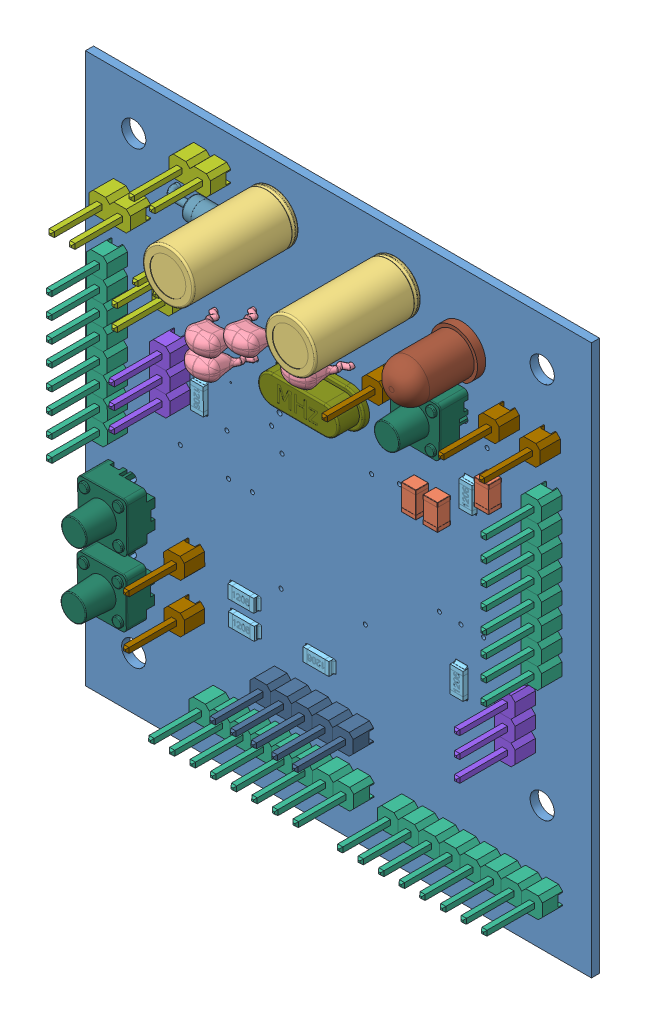
SolidWorks assembly STM32DevBoard, configuration Default. Lengths in mm.
Overall size (62.35 67.78 16.2).
48 component instances, 16 part files, 79 mates.
Components (placement in the parent):
- board^STM32DevBoard-1: board^STM32DevBoard [Default] at origin size (62.35 67.78 1) (virtual)
- CAP 1206-1.8mm^STM32DevBoard-4: CAP 1206-1.8mm^STM32DevBoard [По умолчанию] at (48.0846 53.1145 -0.8) x (1 0 0) z (0 0 -1) size (3.2 1.8 1.6) (virtual)
- CAP 1206-1.8mm^STM32DevBoard-5: CAP 1206-1.8mm^STM32DevBoard [По умолчанию] at (44.5905 35.7089 -0.8) x (1 0 0) z (0 0 -1) size (3.2 1.8 1.6) (virtual)
- CAP 1206-1.8mm^STM32DevBoard-6: CAP 1206-1.8mm^STM32DevBoard [По умолчанию] at (35.6382 31.1408 -0.8) x (0 -1 0) z (0 0 -1) size (3.2 1.8 1.6) (virtual)
- CAP 1206-1.8mm^STM32DevBoard-7: CAP 1206-1.8mm^STM32DevBoard [По умолчанию] at (28.6545 43.2496 -0.8) x (1 0 0) z (0 0 -1) size (3.2 1.8 1.6) (virtual)
- CAP 1206-1.8mm^STM32DevBoard-8: CAP 1206-1.8mm^STM32DevBoard [По умолчанию] at (51.7411 49.9662 1.8) x (0 -1 0) z (0 0 1) size (3.2 1.8 1.6) (virtual)
- CAP 1206-1.8mm^STM32DevBoard-9: CAP 1206-1.8mm^STM32DevBoard [По умолчанию] at (49.0642 49.9662 1.8) x (0 -1 0) z (0 0 1) size (3.2 1.8 1.6) (virtual)
- CAP 1206-1.8mm^STM32DevBoard-10: CAP 1206-1.8mm^STM32DevBoard [По умолчанию] at (58.0295 55.0045 1.8) x (0 -1 0) z (0 0 1) size (3.2 1.8 1.6) (virtual)
- CAP ALTH D-6.3MM L-2.5MM H-13MM^STM32DevBoard-1: CAP ALTH D-6.3MM L-2.5MM H-13MM^STM32DevBoard [По умолчанию] at (31.9223 70.75 1) x (-0.001863 0.999998 0) z (0.999998 0.001863 0) size (6.3 16.2 6.3) (virtual)
- CAP ALTH D-6.3MM L-2.5MM H-13MM^STM32DevBoard-2: CAP ALTH D-6.3MM L-2.5MM H-13MM^STM32DevBoard [По умолчанию] at (46.9823 70.84 1) x (-0.001863 0.999998 0) z (0.999998 0.001863 0) size (6.3 16.2 6.3) (virtual)
- Ceramic Cap, 5mm lead spacing, 4mm width, and 5.5mm tall, v4^STM32DevBoard-1: Ceramic Cap, 5mm lead spacing, 4mm width, and 5.5mm tall, v4^STM32DevBoard [Default] at (24.9777 55.4187 2.2365) x (0.999842 0.017785 0) z (0.017785 -0.999842 0) size (5.76 7.32 2.47) (virtual)
- Ceramic Cap, 5mm lead spacing, 4mm width, and 5.5mm tall, v4^STM32DevBoard-2: Ceramic Cap, 5mm lead spacing, 4mm width, and 5.5mm tall, v4^STM32DevBoard [Default] at (25.0631 58.0527 2.2365) x (0.999985 0.005528 0) z (0.005528 -0.999985 0) size (5.76 7.32 2.47) (virtual)
- Ceramic Cap, 5mm lead spacing, 4mm width, and 5.5mm tall, v4^STM32DevBoard-3: Ceramic Cap, 5mm lead spacing, 4mm width, and 5.5mm tall, v4^STM32DevBoard [Default] at (29.8313 60.5035 2.2365) x (0.999976 0.006978 0) z (0.006978 -0.999976 0) size (5.76 7.32 2.47) (virtual)
- Ceramic Cap, 5mm lead spacing, 4mm width, and 5.5mm tall, v4^STM32DevBoard-4: Ceramic Cap, 5mm lead spacing, 4mm width, and 5.5mm tall, v4^STM32DevBoard [Default] at (36.8824 60.619 2.2365) x (0.999998 -0.001958 0) z (-0.001958 -0.999998 0) size (5.76 7.32 2.47) (virtual)
- Resistor 1206^STM32DevBoard-12: Resistor 1206^STM32DevBoard [Default] at (46.7955 51.7278 0) x (1 0 0) z (0 1 0) size (3.8 0.73 1.65) (virtual)
- Resistor 1206^STM32DevBoard-13: Resistor 1206^STM32DevBoard [Default] at (19.0513 40.7216 0) x (0 -1 0) z (1 0 0) size (3.8 0.73 1.65) (virtual)
- Resistor 1206^STM32DevBoard-14: Resistor 1206^STM32DevBoard [Default] at (50.5897 30.9421 1) x (0 1 0) z (1 0 0) size (3.8 0.73 1.65) (virtual)
- Resistor 1206^STM32DevBoard-15: Resistor 1206^STM32DevBoard [Default] at (26.7586 29.5821 1) x (1 0 0) z (0 -1 0) size (3.8 0.73 1.65) (virtual)
- Resistor 1206^STM32DevBoard-16: Resistor 1206^STM32DevBoard [Default] at (26.6977 32.5396 1) x (1 0 0) z (0 -1 0) size (3.8 0.73 1.65) (virtual)
- Resistor 1206^STM32DevBoard-17: Resistor 1206^STM32DevBoard [Default] at (38.5084 55.8807 0) x (-0.707107 -0.707107 0) z (0.707107 -0.707107 0) size (3.8 0.73 1.65) (virtual)
- Resistor 1206^STM32DevBoard-18: Resistor 1206^STM32DevBoard [Default] at (39.1608 21.8337 1) x (-1 0 0) z (0 1 0) size (3.8 0.73 1.65) (virtual)
- Resistor 1206^STM32DevBoard-19: Resistor 1206^STM32DevBoard [Default] at (47.7723 69.5299 0) x (0 -1 0) z (1 0 0) size (3.8 0.73 1.65) (virtual)
- Resistor 1206^STM32DevBoard-20: Resistor 1206^STM32DevBoard [Default] at (27.1681 48.5004 1) x (0.003826 -0.999993 0) z (-0.999993 -0.003826 0) size (3.8 0.73 1.65) (virtual)
- Resistor 1206^STM32DevBoard-21: Resistor 1206^STM32DevBoard [Default] at (51.7052 51.3196 1) x (0 1 0) z (1 0 0) size (3.8 0.73 1.65) (virtual)
- PLS-8 (DS1021-1x8)^STM32DevBoard-1: PLS-8 (DS1021-1x8)^STM32DevBoard [По умолчанию] at (12.4759 39.0977 3.5) x (1 0.000401 0) z (-0.000401 1 0) size (2.54 11.6 20.32) (virtual)
- PLS-8 (DS1021-1x8)^STM32DevBoard-2: PLS-8 (DS1021-1x8)^STM32DevBoard [По умолчанию] at (65.9964 39.883 3.5) x (1 0.000394 0) z (-0.000394 1 0) size (2.54 11.6 20.32) (virtual)
- PLS-8 (DS1021-1x8)^STM32DevBoard-3: PLS-8 (DS1021-1x8)^STM32DevBoard [По умолчанию] at (48.306 15.4505 3.5) x (0.000403 -1 0) z (1 0.000403 0) size (2.54 11.6 20.32) (virtual)
- PLS-8 (DS1021-1x8)^STM32DevBoard-4: PLS-8 (DS1021-1x8)^STM32DevBoard [По умолчанию] at (42.8461 15.4226 3.5) x (-0.000363 1 0) z (-1 -0.000363 0) size (2.54 11.6 20.32) (virtual)
- PLS-2 (DS1021-1x2)^STM32DevBoard-1: PLS-2 (DS1021-1x2)^STM32DevBoard [По умолчанию] at (20.5402 57.0968 3.5) x (1 0 0) z (0 1 0) size (2.54 11.6 5.08) (virtual)
- PLS-2 (DS1021-1x2)^STM32DevBoard-2: PLS-2 (DS1021-1x2)^STM32DevBoard [По умолчанию] at (15.3155 63.351 3.5) x (0 1 0) z (-1 0 0) size (2.54 11.6 5.08) (virtual)
- PLS-2 (DS1021-1x2)^STM32DevBoard-3: PLS-2 (DS1021-1x2)^STM32DevBoard [По умолчанию] at (25.6276 63.259 3.5) x (0 1 0) z (-1 0 0) size (2.54 11.6 5.08) (virtual)
- PLS-2 (DS1021-1x2)^STM32DevBoard-4: PLS-2 (DS1021-1x2)^STM32DevBoard [По умолчанию] at (25.1771 72.0899 3.5) x (0.016308 0.999867 0) z (-0.999867 0.016308 0) size (2.54 11.6 5.08) (virtual)
- PLS-3 (DS1021-1x3)^STM32DevBoard-1: PLS-3 (DS1021-1x3)^STM32DevBoard [По умолчанию] at (20.19 46.04 3.5) x (1 0 0) z (0 1 0) size (2.54 11.6 7.62) (virtual)
- PLS-1 (DS1021-1x1)^STM32DevBoard-1: PLS-1 (DS1021-1x1)^STM32DevBoard [По умолчанию] at (21.98 29.61 3.5) x (0.999713 0.023974 0) z (-0.023974 0.999713 0) size (2.54 11.6 2.54) (virtual)
- PLS-1 (DS1021-1x1)^STM32DevBoard-2: PLS-1 (DS1021-1x1)^STM32DevBoard [По умолчанию] at (21.98 23.57 3.5) x (1 0 0) z (0 1 0) size (2.54 11.6 2.54) (virtual)
- PLS-1 (DS1021-1x1)^STM32DevBoard-3: PLS-1 (DS1021-1x1)^STM32DevBoard [По умолчанию] at (65.8 63.59 3.5) x (1 0 0) z (0 1 0) size (2.54 11.6 2.54) (virtual)
- PLS-1 (DS1021-1x1)^STM32DevBoard-4: PLS-1 (DS1021-1x1)^STM32DevBoard [По умолчанию] at (60.76 63.59 3.5) x (1 0 0) z (0 1 0) size (2.54 11.6 2.54) (virtual)
- PLS-1 (DS1021-1x1)^STM32DevBoard-5: PLS-1 (DS1021-1x1)^STM32DevBoard [По умолчанию] at (46.42 60.49 3.5) x (1 0 0) z (0 1 0) size (2.54 11.6 2.54) (virtual)
- PLS-3 (DS1021-1x3)^STM32DevBoard-2: PLS-3 (DS1021-1x3)^STM32DevBoard [По умолчанию] at (62.73 30.09 3.5) x (1 0 0) z (0 1 0) size (2.54 11.6 7.62) (virtual)
- PLS-5 (DS1021-1x5)^STM32DevBoard-1: PLS-5 (DS1021-1x5)^STM32DevBoard [По умолчанию] at (32.62 21.25 3.5) x (0 -1 0) z (1 0 0) size (2.54 11.6 12.7) (virtual)
- led_5mm_G^STM32DevBoard-1: led_5mm_G^STM32DevBoard [По умолчанию] at (54.9721 67.93 1) x (0.006307 0.99998 0) z (0 0 1) size (5.4 5.8 11.2) (virtual)
- SOT-223^STM32DevBoard-1: SOT-223^STM32DevBoard [По умолчанию] at (39.1727 70.153 0) x (1 0 0) z (0 1 0) size (7.02 1.8 6.5) (virtual)
- LQFP-48-7x7mm^STM32DevBoard-1: LQFP-48-7x7mm^STM32DevBoard [По умолчанию] at (38.387 39.2514 0) x (0 -1 0) z (1 0 0) size (9.02 1.55 9.02) (virtual)
- DO-41-L=10.16^STM32DevBoard-1: DO-41-L=10.16^STM32DevBoard [Default] at (25.05 67.72 2.3195) x (0 -1 0) z (-1 0 0) size (2.64 5.12 11.02) (virtual)
- Tactile Switch^STM32DevBoard-1: Tactile Switch^STM32DevBoard [Default] at (14.1225 31.3822 1) x (-0.011523 0.999934 0) z (0.999934 0.011523 0) size (6 8.5 6) (virtual)
- Tactile Switch^STM32DevBoard-2: Tactile Switch^STM32DevBoard [Default] at (14.0599 23.2867 1) x (-0.011644 0.999932 0) z (0.999932 0.011644 0) size (6 8.5 6) (virtual)
- Tactile Switch^STM32DevBoard-3: Tactile Switch^STM32DevBoard [Default] at (52.6634 60.8907 1) x (0.999927 -0.012104 0) z (-0.012104 -0.999927 0) size (6 8.5 6) (virtual)
- Crystal Oscillator^STM32DevBoard-1: Crystal Oscillator^STM32DevBoard [Default] at (35.65 55.14 1) x (0.999999 -0.001678 0) z (0 0 1) size (10.95 4.6 6.2) (virtual)
Mates (geometry in assembly coordinates):
- Coincident1: coincident anti-aligned: plane of отладочная_на_арм-1 through (0 0 1) normal (0 0 1); plane of PLS-8 (DS1021-1x8)-1 through (12.4759 39.0977 1) normal (0 0 -1)
- Tangent1: tangent: cylinder of отладочная_на_арм-1 through (12.47 39.1 1) axis (0 0 -1) radius 0.45; line of PLS-8 (DS1021-1x8)-1 through (12.1561 38.7776 9.3616) axis (0 0 -1)
- Tangent2: tangent: cylinder of отладочная_на_арм-1 through (12.47 56.88 1) axis (0 0 -1) radius 0.455; line of PLS-8 (DS1021-1x8)-1 through (12.1489 56.5576 9.3616) axis (0 0 -1)
- Coincident2: coincident anti-aligned: plane of отладочная_на_арм-1 through (0 0 1) normal (0 0 1); plane of PLS-8 (DS1021-1x8)-4 through (42.8461 15.4226 1) normal (0 0 -1)
- Coincident3: coincident anti-aligned: plane of отладочная_на_арм-1 through (0 0 1) normal (0 0 1); plane of PLS-8 (DS1021-1x8)-3 through (48.306 15.4505 1) normal (0 0 -1)
- Coincident4: coincident anti-aligned: plane of отладочная_на_арм-1 through (0 0 1) normal (0 0 1); plane of PLS-8 (DS1021-1x8)-2 through (65.9964 39.883 1) normal (0 0 -1)
- Tangent3: tangent: cylinder of отладочная_на_арм-1 through (65.99 39.88 1) axis (0 0 -1) radius 0.455; line of PLS-8 (DS1021-1x8)-2 through (66.3165 39.5631 9.3616) axis (0 0 -1)
- Tangent4: tangent: cylinder of отладочная_на_арм-1 through (65.99 57.66 1) axis (0 0 -1) radius 0.45; line of PLS-8 (DS1021-1x8)-2 through (66.3095 57.3431 9.3616) axis (0 0 -1)
- Tangent5: tangent: cylinder of отладочная_на_арм-1 through (25.1 15.45 1) axis (0 0 -1) radius 0.455; line of PLS-8 (DS1021-1x8)-4 through (25.3862 15.0963 1.5649) axis (0 0 -1)
- Tangent6: tangent: cylinder of отладочная_на_арм-1 through (42.88 15.45 1) axis (0 0 -1) radius 0.45; line of PLS-8 (DS1021-1x8)-4 through (43.1662 15.1028 1.5649) axis (0 0 -1)
- Tangent7: tangent: cylinder of отладочная_на_арм-1 through (66.09 15.45 1) axis (0 0 -1) radius 0.45; line of PLS-8 (DS1021-1x8)-3 through (65.7662 15.1375 1.5649) axis (0 0 -1)
- Tangent8: tangent: cylinder of отладочная_на_арм-1 through (48.31 15.45 1) axis (0 0 -1) radius 0.455; line of PLS-8 (DS1021-1x8)-3 through (47.9862 15.1304 1.5649) axis (0 0 -1)
- Coincident5: coincident anti-aligned: plane of отладочная_на_арм-1 through (0 0 1) normal (0 0 1); plane of PLS-2 (DS1021-1x2)-1 through (20.5402 57.0968 1) normal (0 0 -1)
- Tangent9: tangent: cylinder of отладочная_на_арм-1 through (20.53 57.11 1) axis (0 0 -1) radius 0.455; line of PLS-2 (DS1021-1x2)-1 through (20.2202 56.7768 1.5649) axis (0 0 -1)
- Tangent10: tangent: cylinder of отладочная_на_арм-1 through (20.53 59.65 1) axis (0 0 -1) radius 0.455; line of PLS-2 (DS1021-1x2)-1 through (20.2202 59.3168 1.5649) axis (0 0 -1)
- Coincident6: coincident anti-aligned: plane of отладочная_на_арм-1 through (0 0 1) normal (0 0 1); plane of PLS-2 (DS1021-1x2)-2 through (15.3155 63.351 1) normal (0 0 -1)
- Tangent11: tangent: cylinder of отладочная_на_арм-1 through (12.78 63.35 1) axis (0 0 -1) radius 0.455; line of PLS-2 (DS1021-1x2)-2 through (12.4555 63.031 1.5649) axis (0 0 -1)
- Tangent12: tangent: cylinder of отладочная_на_арм-1 through (15.32 63.35 1) axis (0 0 -1) radius 0.455; line of PLS-2 (DS1021-1x2)-2 through (14.9955 63.031 1.5649) axis (0 0 -1)
- Coincident7: coincident anti-aligned: plane of отладочная_на_арм-1 through (0 0 1) normal (0 0 1); plane of PLS-2 (DS1021-1x2)-3 through (25.6276 63.259 1) normal (0 0 -1)
- Tangent13: tangent: cylinder of отладочная_на_арм-1 through (25.63 63.26 1) axis (0 0 -1) radius 0.455; line of PLS-2 (DS1021-1x2)-3 through (25.3076 62.939 1.5649) axis (0 0 -1)
- Tangent14: tangent: cylinder of отладочная_на_арм-1 through (23.09 63.26 1) axis (0 0 -1) radius 0.455; line of PLS-2 (DS1021-1x2)-3 through (22.7676 62.939 1.5649) axis (0 0 -1)
- Coincident8: coincident anti-aligned: plane of отладочная_на_арм-1 through (0 0 1) normal (0 0 1); plane of PLS-2 (DS1021-1x2)-4 through (25.1771 72.0899 1) normal (0 0 -1)
- Tangent15: tangent: cylinder of отладочная_на_арм-1 through (22.66 72.11 1) axis (0 0 -1) radius 0.455; line of PLS-2 (DS1021-1x2)-4 through (22.3123 71.8165 1.5649) axis (0 0 -1)
- Tangent16: tangent: cylinder of отладочная_на_арм-1 through (25.2 72.11 1) axis (0 0 -1) radius 0.455; line of PLS-2 (DS1021-1x2)-4 through (24.8624 72.415 1.5649) axis (0 0 -1)
- Coincident9: coincident anti-aligned: plane of отладочная_на_арм-1 through (0 0 1) normal (0 0 1); plane of PLS-3 (DS1021-1x3)-1 through (20.19 46.04 1) normal (0 0 -1)
- Coincident10: coincident anti-aligned: plane of отладочная_на_арм-1 through (0 0 1) normal (0 0 1); plane of PLS-1 (DS1021-1x1)-1 through (21.98 29.61 1) normal (0 0 -1)
- Coincident11: coincident anti-aligned: plane of отладочная_на_арм-1 through (0 0 1) normal (0 0 1); plane of PLS-1 (DS1021-1x1)-2 through (21.98 23.57 1) normal (0 0 -1)
- Concentric1: concentric anti-aligned: cylinder of отладочная_на_арм-1 through (21.98 29.61 1) axis (0 0 -1) radius 0.455; line of PLS-1 (DS1021-1x1)-1 through (21.98 29.61 -0.7609) axis (0 0 1)
- Concentric2: concentric anti-aligned: cylinder of отладочная_на_арм-1 through (21.98 23.57 1) axis (0 0 -1) radius 0.455; line of PLS-1 (DS1021-1x1)-2 through (21.98 23.57 -0.7609) axis (0 0 1)
- Coincident12: coincident anti-aligned: plane of отладочная_на_арм-1 through (0 0 1) normal (0 0 1); plane of PLS-1 (DS1021-1x1)-3 through (65.8 63.59 1) normal (0 0 -1)
- Concentric3: concentric anti-aligned: cylinder of отладочная_на_арм-1 through (65.8 63.59 1) axis (0 0 -1) radius 0.455; line of PLS-1 (DS1021-1x1)-3 through (65.8 63.59 -0.7609) axis (0 0 1)
- Concentric4: concentric anti-aligned: cylinder of отладочная_на_арм-1 through (60.76 63.59 1) axis (0 0 -1) radius 0.455; line of PLS-1 (DS1021-1x1)-4 through (60.76 63.59 -0.7609) axis (0 0 1)
- Coincident13: coincident anti-aligned: plane of отладочная_на_арм-1 through (0 0 1) normal (0 0 1); plane of PLS-1 (DS1021-1x1)-4 through (60.76 63.59 1) normal (0 0 -1)
- Coincident14: coincident anti-aligned: plane of отладочная_на_арм-1 through (0 0 1) normal (0 0 1); plane of PLS-1 (DS1021-1x1)-5 through (46.42 60.49 1) normal (0 0 -1)
- Concentric5: concentric anti-aligned: cylinder of отладочная_на_арм-1 through (46.42 60.49 1) axis (0 0 -1) radius 0.455; line of PLS-1 (DS1021-1x1)-5 through (46.42 60.49 -0.7609) axis (0 0 1)
- Concentric6: concentric aligned: cylinder of отладочная_на_арм-1 through (20.19 46.04 1) axis (0 0 -1) radius 0.45; line of PLS-3 (DS1021-1x3)-1 through (20.19 46.04 3.5) axis (0 0 -1)
- Concentric7: concentric aligned: cylinder of отладочная_на_арм-1 through (20.19 51.12 1) axis (0 0 -1) radius 0.45; line of PLS-3 (DS1021-1x3)-1 through (20.19 51.12 3.5) axis (0 0 -1)
- Coincident15: coincident anti-aligned: plane of отладочная_на_арм-1 through (0 0 1) normal (0 0 1); plane of PLS-3 (DS1021-1x3)-2 through (62.73 35.17 1) normal (0 0 -1)
- Concentric8: concentric aligned: cylinder of отладочная_на_арм-1 through (62.73 30.09 1) axis (0 0 -1) radius 0.45; line of PLS-3 (DS1021-1x3)-2 through (62.73 30.09 3.5) axis (0 0 -1)
- Concentric9: concentric aligned: cylinder of отладочная_на_арм-1 through (62.73 35.17 1) axis (0 0 -1) radius 0.455; line of PLS-3 (DS1021-1x3)-2 through (62.73 35.17 3.5) axis (0 0 -1)
- Coincident16: coincident anti-aligned: plane of отладочная_на_арм-1 through (0 0 1) normal (0 0 1); plane of PLS-5 (DS1021-1x5)-1 through (42.78 21.25 1) normal (0 0 -1)
- Concentric10: concentric aligned: cylinder of отладочная_на_арм-1 through (32.62 21.25 1) axis (0 0 -1) radius 0.45; line of PLS-5 (DS1021-1x5)-1 through (32.62 21.25 3.5) axis (0 0 -1)
- Concentric11: concentric anti-aligned: cylinder of отладочная_на_арм-1 through (42.78 21.25 1) axis (0 0 -1) radius 0.455; line of PLS-5 (DS1021-1x5)-1 through (42.78 21.25 1) axis (0 0 1)
- Coincident26: coincident anti-aligned: plane of отладочная_на_арм-1 through (0 0 1) normal (0 0 1); plane of led_5mm_G-1 through (54.9721 67.93 1) normal (0 0 -1)
- Concentric12: concentric aligned: cylinder of отладочная_на_арм-1 through (54.98 69.18 1) axis (0 0 -1) radius 0.405; cylinder of led_5mm_G-1 through (54.98 69.18 1) axis (0 0 -1) radius 0.25
- Coincident27: coincident anti-aligned: plane of отладочная_на_арм-1 through (0 0 1) normal (0 0 1); plane of CAP ALTH D-6.3MM L-2.5MM H-13MM-1 through (31.9223 70.75 1) normal (0 0 -1)
- Concentric15: concentric anti-aligned: cylinder of отладочная_на_арм-1 through (31.92 72 1) axis (0 0 -1) radius 0.405; cylinder of CAP ALTH D-6.3MM L-2.5MM H-13MM-1 through (31.92 72 -2) axis (0 0 1) radius 0.25
- Coincident28: coincident anti-aligned: plane of отладочная_на_арм-1 through (0 0 1) normal (0 0 1); plane of CAP ALTH D-6.3MM L-2.5MM H-13MM-2 through (46.9823 70.84 1) normal (0 0 -1)
- Concentric16: concentric anti-aligned: cylinder of отладочная_на_арм-1 through (46.98 72.09 1) axis (0 0 -1) radius 0.405; cylinder of CAP ALTH D-6.3MM L-2.5MM H-13MM-2 through (46.98 72.09 -2) axis (0 0 1) radius 0.25
- Coincident29: coincident anti-aligned: plane of отладочная_на_арм-1 through (0 0 0) normal (0 0 -1); plane of SOT-223-1 through (41.6727 71.653 0) normal (0 0 1)
- Coincident30: coincident anti-aligned: plane of отладочная_на_арм-1 through (0 0 0) normal (0 0 -1); plane of CAP 1206-1.8mm-5 through (46.1905 33.9089 0) normal (0 0 1)
- Coincident31: coincident anti-aligned: plane of отладочная_на_арм-1 through (0 0 0) normal (0 0 -1); plane of CAP 1206-1.8mm-3 through (33.8382 29.5408 0) normal (0 0 1)
- Coincident32: coincident anti-aligned: plane of отладочная_на_арм-1 through (0 0 0) normal (0 0 -1); plane of CAP 1206-1.8mm-6 through (30.2545 41.4496 0) normal (0 0 1)
- Coincident33: coincident anti-aligned: plane of отладочная_на_арм-1 through (0 0 0) normal (0 0 -1); plane of CAP 1206-1.8mm-4 through (46.4846 51.3145 0) normal (0 0 1)
- Coincident34: coincident anti-aligned: plane of отладочная_на_арм-1 through (0 0 1) normal (0 0 1); plane of CAP 1206-1.8mm-7 through (50.8642 48.3662 1) normal (0 0 -1)
- Coincident35: coincident anti-aligned: plane of отладочная_на_арм-1 through (0 0 1) normal (0 0 1); plane of CAP 1206-1.8mm-8 through (53.5411 48.3662 1) normal (0 0 -1)
- Coincident36: coincident anti-aligned: plane of отладочная_на_арм-1 through (0 0 1) normal (0 0 1); plane of CAP 1206-1.8mm-9 through (59.8295 53.4045 1) normal (0 0 -1)
- Coincident37: coincident: plane of отладочная_на_арм-1 through (0 0 0) normal (0 0 -1); line of LQFP-48-7x7mm-1 through (42.887 41.8914 0) axis (0 1 0)
- Coincident38: coincident: plane of отладочная_на_арм-1 through (0 0 0) normal (0 0 -1); line of LQFP-48-7x7mm-1 through (41.027 34.7514 0) axis (1 0 0)
- Parallel1: parallel anti-aligned: plane of отладочная_на_арм-1 through (8.56 0 1) normal (-1 0 0); plane of LQFP-48-7x7mm-1 through (38.387 39.2514 0) normal (1 0 0)
- Concentric17: concentric aligned: cylinder of отладочная_на_арм-1 through (30.13 67.72 1) axis (0 0 -1) radius 0.3; cylinder of DO-41-L=10.16-1 through (30.13 67.72 1.3195) axis (0 0 -1) radius 0.43
- Concentric18: concentric aligned: cylinder of отладочная_на_арм-1 through (19.97 67.72 1) axis (0 0 -1) radius 0.3; cylinder of DO-41-L=10.16-1 through (19.97 67.72 1.3195) axis (0 0 -1) radius 0.43
- Tangent21: tangent anti-aligned: plane of отладочная_на_арм-1 through (0 0 1) normal (0 0 1); cylinder of DO-41-L=10.16-1 through (23.7005 67.72 2.3195) axis (-1 0 0) radius 1.3195
- Coincident39: coincident anti-aligned: plane of отладочная_на_арм-1 through (0 0 1) normal (0 0 1); plane of Tactile Switch-1 through (14.1225 31.3822 1) normal (0 0 -1)
- Coincident40: coincident anti-aligned: plane of отладочная_на_арм-1 through (0 0 1) normal (0 0 1); plane of Tactile Switch-2 through (14.0599 23.2867 1) normal (0 0 -1)
- Tangent22: tangent: cylinder of отладочная_на_арм-1 through (14.32 33.88 1) axis (0 0 -1) radius 0.51; line of Tactile Switch-1 through (14.3879 34.3855 -0.5) axis (0 0 1)
- Tangent23: tangent: cylinder of отладочная_на_арм-1 through (14.32 25.78 1) axis (0 0 -1) radius 0.51; line of Tactile Switch-2 through (14.325 26.29 -0.5) axis (0 0 1)
- Coincident41: coincident anti-aligned: plane of отладочная_на_арм-1 through (0 0 1) normal (0 0 1); plane of Tactile Switch-3 through (52.6634 60.8907 1) normal (0 0 -1)
- Tangent24: tangent: cylinder of отладочная_на_арм-1 through (50.17 60.63 1) axis (0 0 -1) radius 0.51; line of Tactile Switch-3 through (49.66 60.6271 -0.5) axis (0 0 1)
- Coincident42: coincident anti-aligned: plane of отладочная_на_арм-1 through (0 0 1) normal (0 0 1); plane of Crystal Oscillator-1 through (38.095 55.1359 1) normal (0 0 -1)
- Concentric19: concentric aligned: cylinder of отладочная_на_арм-1 through (35.65 55.14 1) axis (0 0 -1) radius 0.3; cylinder of Crystal Oscillator-1 through (35.65 55.14 1) axis (0 0 -1) radius 0.24
- Concentric20: concentric anti-aligned: cylinder of отладочная_на_арм-1 through (24.5 54.16 1) axis (0 0 -1) radius 0.3; cylinder of Ceramic Cap, 5mm lead spacing, 4mm width, and 5.5mm tall, v4-1 through (24.5 54.16 -1.0635) axis (0 0 1) radius 0.325
- Coincident43: coincident: point of отладочная_на_арм-1; unknown of Ceramic Cap, 5mm lead spacing, 4mm width, and 5.5mm tall, v4-1
- Concentric21: concentric anti-aligned: cylinder of отладочная_на_арм-1 through (24.57 56.8 1) axis (0 0 -1) radius 0.3; cylinder of Ceramic Cap, 5mm lead spacing, 4mm width, and 5.5mm tall, v4-2 through (24.57 56.8 -1.0635) axis (0 0 1) radius 0.325
- Coincident44: coincident: plane of отладочная_на_арм-1 through (0 0 1) normal (0 0 1); unknown of Ceramic Cap, 5mm lead spacing, 4mm width, and 5.5mm tall, v4-2
- Concentric22: concentric anti-aligned: cylinder of отладочная_на_арм-1 through (36.38 59.37 1) axis (0 0 -1) radius 0.3; cylinder of Ceramic Cap, 5mm lead spacing, 4mm width, and 5.5mm tall, v4-4 through (36.38 59.37 -1.0635) axis (0 0 1) radius 0.325
- Coincident45: coincident: plane of отладочная_на_арм-1 through (0 0 1) normal (0 0 1); unknown of Ceramic Cap, 5mm lead spacing, 4mm width, and 5.5mm tall, v4-4
- Concentric23: concentric anti-aligned: cylinder of отладочная_на_арм-1 through (29.34 59.25 1) axis (0 0 -1) radius 0.3; cylinder of Ceramic Cap, 5mm lead spacing, 4mm width, and 5.5mm tall, v4-3 through (29.34 59.25 -1.0635) axis (0 0 1) radius 0.325
- Coincident46: coincident: plane of отладочная_на_арм-1 through (0 0 1) normal (0 0 1); point of Ceramic Cap, 5mm lead spacing, 4mm width, and 5.5mm tall, v4-3
